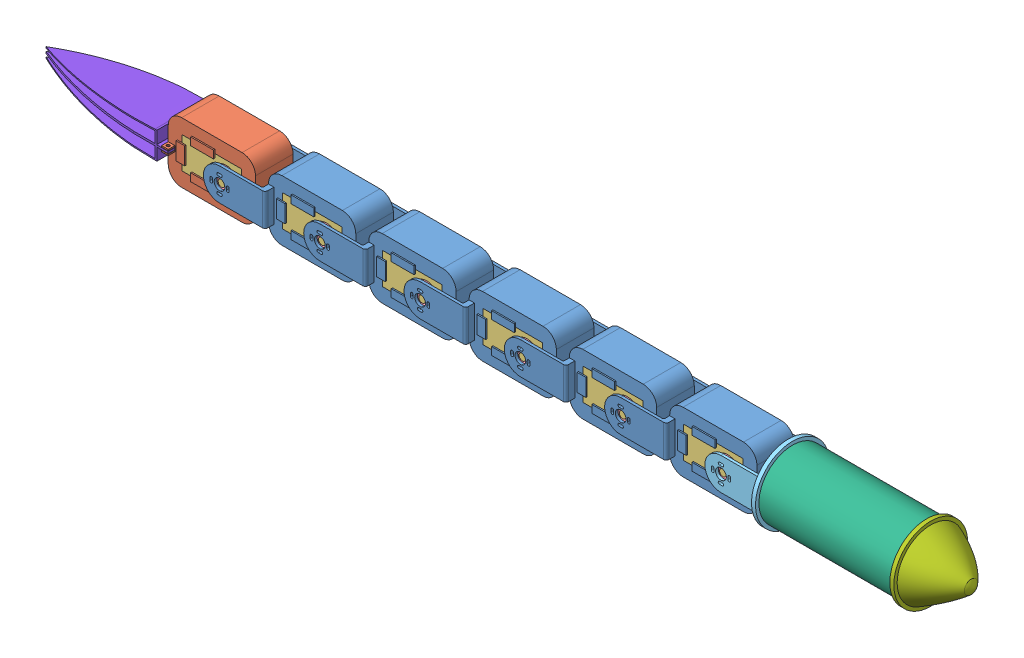
SolidWorks assembly bus_assembly_2, configuration 預設. Lengths in mm.
Overall size (691.28 55 55).
28 component instances, 8 part files, 89 mates.
Components (placement in the parent):
- bus2-1: bus2 [預設] at (12.4546 -2.1213 92.75) size (107 45 40.5)
- bus2-2: bus2 [預設] at (-62.2454 -2.1213 92.75) size (107 45 40.5)
- bus2-3: bus2 [預設] at (-286.3454 -2.1213 92.75) size (107 45 40.5)
- bus2-4: bus2 [預設] at (-136.9454 -2.1213 92.75) size (107 45 40.5)
- bus2-5: bus2 [預設] at (-211.6454 -2.1213 92.75) size (107 45 40.5)
- bus2_tail-1: bus2_tail [預設] at (-361.0454 -2.1213 92.75) size (65 45 38)
- bus_servo-1: bus_servo [預設] at (-368.5322 -13.6144 92.75) x (1 0 0) z (0 -1 0) size (44.4 38 23.4)
- bus_servo_cicrcle1-1: bus_servo_cicrcle1 [預設] at (-376.28 -2.2213 122.25) size (20 20 3)
- bus_servo_cicrcle1-2: bus_servo_cicrcle1 [預設] at (-376.28 -2.1213 88.75) size (20 20 3)
- bus_servo-2: bus_servo [預設] at (-293.8322 -13.6144 92.75) x (1 0 0) z (0 -1 0) size (44.4 38 23.4)
- bus_servo-3: bus_servo [預設] at (-219.1322 -13.6144 92.75) x (1 0 0) z (0 -1 0) size (44.4 38 23.4)
- bus_servo-4: bus_servo [預設] at (-144.4322 9.3718 120.75) x (1 0 0) z (0 1 0) size (44.4 38 23.4)
- bus_servo-5: bus_servo [預設] at (-69.7322 -13.6144 92.75) x (1 0 0) z (0 -1 0) size (44.4 38 23.4)
- bus_servo-6: bus_servo [預設] at (4.9678 -13.6144 92.75) x (1 0 0) z (0 -1 0) size (44.4 38 23.4)
- bus_servo_cicrcle1-3: bus_servo_cicrcle1 [預設] at (-301.58 -2.1213 122.25) size (20 20 3)
- bus_servo_cicrcle1-4: bus_servo_cicrcle1 [預設] at (-301.58 -2.1213 88.75) size (20 20 3)
- bus_servo_cicrcle1-5: bus_servo_cicrcle1 [預設] at (-226.88 -2.1213 88.75) size (20 20 3)
- bus_servo_cicrcle1-6: bus_servo_cicrcle1 [預設] at (-226.88 -2.1213 122.25) size (20 20 3)
- bus_servo_cicrcle1-7: bus_servo_cicrcle1 [預設] at (-152.18 -2.1213 122.25) size (20 20 3)
- bus_servo_cicrcle1-8: bus_servo_cicrcle1 [預設] at (-152.18 -2.1213 88.75) size (20 20 3)
- bus_servo_cicrcle1-9: bus_servo_cicrcle1 [預設] at (-77.48 -2.1213 122.25) size (20 20 3)
- bus_servo_cicrcle1-10: bus_servo_cicrcle1 [預設] at (-77.48 -2.1213 88.75) size (20 20 3)
- bus_servo_cicrcle1-11: bus_servo_cicrcle1 [預設] at (-2.78 -2.1213 88.75) size (20 20 3)
- bus_servo_cicrcle1-12: bus_servo_cicrcle1 [預設] at (-2.78 -2.1213 122.25) x (0 1 0) z (0 0 1) size (20 20 3)
- bus_lib_tail-1: bus_lib_tail [預設] at (30.22 -2.1213 107) x (0 1 0) z (0 0 -1) size (55 65 55)
- bus_body-1: bus_body [預設] at (30.22 -2.1213 107) x (0 -0.027366 -0.999625) z (0 -0.999625 0.027366) size (50 100 50)
- bus_lib_head_1-1: bus_lib_head_1 [預設] at (130.22 -2.1213 107) x (0 1 0) z (0 0 1) size (55 54.98 55)
- bus_final_tail-2: bus_final_tail [預設] at (-425.0707 -2.1213 107.4806) x (-1 0 -0.00071) z (0 -1 0) size (110.1 38.13 25.31)
Mates (geometry in assembly coordinates):
- 重合/共線/共點1: coincident: plane of bus2-1 through (12.4546 -2.1213 120.75) normal (0 0 1); plane of bus2-2 through (-62.2454 -2.1213 120.75) normal (0 0 1)
- 重合/共線/共點2: coincident: plane of bus2-1 through (-47.48 20.3787 120.75) normal (0 1 0); plane of bus2-2 through (-122.18 20.3787 120.75) normal (0 1 0)
- 重合/共線/共點3: coincident: plane of bus2-3 through (-286.3454 -2.1213 120.75) normal (0 0 1); plane of bus2-2 through (-62.2454 -2.1213 120.75) normal (0 0 1)
- 重合/共線/共點4: coincident: plane of bus2-2 through (-122.18 20.3787 120.75) normal (0 1 0); plane of bus2-3 through (-346.28 20.3787 120.75) normal (0 1 0)
- 重合/共線/共點5: coincident: plane of bus2-3 through (-346.28 20.3787 120.75) normal (0 1 0); plane of bus2-4 through (-196.88 20.3787 120.75) normal (0 1 0)
- 重合/共線/共點6: coincident: plane of bus2-3 through (-286.3454 -2.1213 120.75) normal (0 0 1); plane of bus2-4 through (-136.9454 -2.1213 120.75) normal (0 0 1)
- 重合/共線/共點9: coincident: plane of bus2-3 through (-346.28 20.3787 120.75) normal (0 1 0); plane of bus2-5 through (-271.58 20.3787 120.75) normal (0 1 0)
- 重合/共線/共點10: coincident: plane of bus2-3 through (-286.3454 -2.1213 120.75) normal (0 0 1); plane of bus2-5 through (-211.6454 -2.1213 120.75) normal (0 0 1)
- 重合/共線/共點11: coincident: plane of bus2-3 through (-286.3454 -2.1213 120.75) normal (0 0 1); plane of bus2_tail-1 through (-361.0454 -2.1213 120.75) normal (0 0 1)
- 重合/共線/共點12: coincident: plane of bus2-3 through (-346.28 20.3787 120.75) normal (0 1 0); plane of bus2_tail-1 through (-420.98 20.3787 120.75) normal (0 1 0)
- 同軸心1: concentric: cylinder of bus2_tail-1 through (-418.48 2.8787 123.25) axis (0 -1 0) radius 1.1; cylinder of ? through (-418.48 -1.3713 123.25) axis (0 -1 0) radius 1.1
- 同軸心2: concentric: cylinder of bus2_tail-1 through (-418.48 2.8787 90.25) axis (0 -1 0) radius 1.1; cylinder of ? through (-418.48 -1.3713 90.25) axis (0 -1 0) radius 1.1
- 平行相距1: distance = 0.25 mm: line of ? through (-415.9818 -1.3713 125.7518) axis (-1 0 -0.00071); line of bus2_tail-1 through (-420.98 -1.1213 125.75) axis (1 0 0)
- 重合/共線/共點13: coincident: plane of bus2_tail-1 through (-410.68 -13.8213 131.75) normal (0 1 0); plane of bus_servo-1 through (-410.68 -13.8213 120.75) normal (0 -1 0)
- 重合/共線/共點14: coincident: plane of bus2_tail-1 through (-366.28 9.5787 131.75) normal (-1 0 0); plane of bus_servo-1 through (-366.28 9.5787 120.75) normal (1 0 0)
- 重合/共線/共點17: coincident: plane of bus2_tail-1 through (-361.0454 -2.1213 120.75) normal (0 0 1); plane of bus_servo-1 through (-368.5322 -13.6144 120.75) normal (0 0 1)
- 重合/共線/共點18: coincident: plane of bus2-3 through (-377.33 2.9787 86.75) normal (0 1 0); plane of bus_servo_cicrcle1-1 through (-377.33 2.9787 126.25) normal (0 1 0)
- 平行2: parallel: plane of bus2-3 through (-377.33 -9.3213 86.75) normal (0 1 0); plane of bus_servo_cicrcle1-1 through (-377.33 -9.4213 126.25) normal (0 1 0)
- 重合/共線/共點21: coincident: plane of bus2-3 through (-383.48 -1.0713 86.75) normal (1 0 0); plane of bus_servo_cicrcle1-1 through (-383.48 -1.1713 126.25) normal (1 0 0)
- 平行3: parallel: cylinder of bus2-3 through (-376.28 -2.1213 125.25) axis (0 0 1) radius 4; cylinder of bus_servo_cicrcle1-1 through (-376.28 -2.2213 126.25) axis (0 0 -1) radius 4
- 重合/共線/共點22: coincident: plane of bus2-3 through (-376.28 -2.1213 125.25) normal (0 0 -1); plane of bus_servo_cicrcle1-1 through (-376.28 -2.2213 125.25) normal (0 0 1)
- 重合/共線/共點23: coincident: plane of bus2-3 through (-376.28 -2.1213 88.75) normal (0 0 1); plane of bus_servo_cicrcle1-2 through (-376.28 -2.1213 88.75) normal (0 0 -1)
- 同軸心5: concentric: cylinder of bus2-3 through (-376.28 -2.1213 86.75) axis (0 0 1) radius 3.7; cylinder of bus_servo_cicrcle1-2 through (-376.28 -2.1213 92.75) axis (0 0 -1) radius 4
- 同軸心8: concentric: cylinder of bus2-3 through (-376.28 -2.1213 86.75) axis (0 0 1) radius 3.7; cylinder of bus_servo-1 through (-376.28 -2.1213 87.75) axis (0 0 1) radius 2.5
- 重合/共線/共點24: coincident: plane of bus2-3 through (-335.98 -13.8213 131.75) normal (0 1 0); plane of bus_servo-2 through (-335.98 -13.8213 120.75) normal (0 -1 0)
- 重合/共線/共點25: coincident: plane of bus2-3 through (-335.98 9.5787 131.75) normal (1 0 0); plane of bus_servo-2 through (-335.98 9.5787 120.75) normal (-1 0 0)
- 重合/共線/共點26: coincident: plane of bus2-3 through (-286.3454 -2.1213 92.75) normal (0 0 -1); plane of bus_servo-2 through (-293.8322 -13.6144 92.75) normal (0 0 -1)
- 重合/共線/共點27: coincident: plane of bus2-5 through (-261.28 -13.8213 131.75) normal (0 1 0); plane of bus_servo-3 through (-261.28 -13.8213 120.75) normal (0 -1 0)
- 重合/共線/共點28: coincident: plane of bus2-5 through (-261.28 9.5787 131.75) normal (1 0 0); plane of bus_servo-3 through (-261.28 9.5787 120.75) normal (-1 0 0)
- 重合/共線/共點29: coincident: plane of bus2-5 through (-211.6454 -2.1213 92.75) normal (0 0 -1); plane of bus_servo-3 through (-219.1322 -13.6144 92.75) normal (0 0 -1)
- 重合/共線/共點30: coincident: plane of bus2-2 through (-111.88 9.5787 131.75) normal (0 -1 0); plane of bus_servo-4 through (-186.58 9.5787 92.75) normal (0 1 0)
- 重合/共線/共點31: coincident: plane of bus2-4 through (-142.18 9.5787 131.75) normal (-1 0 0); plane of bus_servo-4 through (-142.18 -13.8213 92.75) normal (1 0 0)
- 重合/共線/共點32: coincident: plane of bus2-4 through (-136.9454 -2.1213 120.75) normal (0 0 1); plane of bus_servo-4 through (-144.4322 9.3718 120.75) normal (0 0 1)
- 重合/共線/共點37: coincident: plane of bus2-2 through (-111.88 9.5787 131.75) normal (0 -1 0); plane of bus_servo-5 through (-111.88 9.5787 120.75) normal (0 1 0)
- 重合/共線/共點38: coincident: plane of bus2-2 through (-67.48 9.5787 131.75) normal (-1 0 0); plane of bus_servo-5 through (-67.48 9.5787 120.75) normal (1 0 0)
- 重合/共線/共點40: coincident: plane of bus2-2 through (-62.2454 -2.1213 120.75) normal (0 0 1); plane of bus_servo-5 through (-69.7322 -13.6144 120.75) normal (0 0 1)
- 重合/共線/共點42: coincident: plane of bus2-1 through (12.4546 -2.1213 120.75) normal (0 0 1); plane of bus_servo-6 through (4.9678 -13.6144 120.75) normal (0 0 1)
- 重合/共線/共點43: coincident: plane of bus2-1 through (-37.18 9.5787 131.75) normal (1 0 0); plane of bus_servo-6 through (-37.18 9.5787 120.75) normal (-1 0 0)
- 重合/共線/共點44: coincident: plane of bus2-1 through (-37.18 9.5787 131.75) normal (0 -1 0); plane of bus_servo-6 through (-37.18 9.5787 120.75) normal (0 1 0)
- 同軸心9: concentric: cylinder of bus2-5 through (-301.58 -2.1213 125.25) axis (0 0 1) radius 4; cylinder of bus_servo_cicrcle1-3 through (-301.58 -2.1213 126.25) axis (0 0 -1) radius 4
- 重合/共線/共點45: coincident: plane of bus2-5 through (-301.58 -2.1213 125.25) normal (0 0 -1); plane of bus_servo_cicrcle1-3 through (-301.58 -2.1213 125.25) normal (0 0 1)
- 同軸心10: concentric: cylinder of bus2-5 through (-301.58 -2.1213 86.75) axis (0 0 1) radius 3.7; cylinder of bus_servo_cicrcle1-4 through (-301.58 -2.1213 92.75) axis (0 0 -1) radius 4
- 重合/共線/共點46: coincident: plane of bus2-5 through (-301.58 -2.1213 88.75) normal (0 0 1); plane of bus_servo_cicrcle1-4 through (-301.58 -2.1213 88.75) normal (0 0 -1)
- 同軸心11: concentric: cylinder of bus2-4 through (-226.88 -2.1213 125.25) axis (0 0 1) radius 4; cylinder of bus_servo_cicrcle1-6 through (-226.88 -2.1213 126.25) axis (0 0 -1) radius 4
- 重合/共線/共點47: coincident: plane of bus2-4 through (-226.88 -2.1213 125.25) normal (0 0 -1); plane of bus_servo_cicrcle1-6 through (-226.88 -2.1213 125.25) normal (0 0 1)
- 同軸心12: concentric: cylinder of bus2-4 through (-226.88 -2.1213 86.75) axis (0 0 1) radius 3.7; cylinder of bus_servo_cicrcle1-5 through (-226.88 -2.1213 92.75) axis (0 0 -1) radius 4
- 重合/共線/共點48: coincident: plane of bus2-4 through (-226.88 -2.1213 88.75) normal (0 0 1); plane of bus_servo_cicrcle1-5 through (-226.88 -2.1213 88.75) normal (0 0 -1)
- 同軸心13: concentric: cylinder of bus2-2 through (-152.18 -2.1213 86.75) axis (0 0 1) radius 3.7; cylinder of bus_servo_cicrcle1-8 through (-152.18 -2.1213 92.75) axis (0 0 -1) radius 4
- 重合/共線/共點49: coincident: plane of bus2-2 through (-152.18 -2.1213 88.75) normal (0 0 1); plane of bus_servo_cicrcle1-8 through (-152.18 -2.1213 88.75) normal (0 0 -1)
- 同軸心14: concentric: cylinder of bus2-2 through (-152.18 -2.1213 125.25) axis (0 0 1) radius 4; cylinder of bus_servo_cicrcle1-7 through (-152.18 -2.1213 126.25) axis (0 0 -1) radius 4
- 重合/共線/共點51: coincident: plane of bus2-2 through (-152.18 -2.1213 125.25) normal (0 0 -1); plane of bus_servo_cicrcle1-7 through (-152.18 -2.1213 125.25) normal (0 0 1)
- 重合/共線/共點52: coincident: plane of bus2-5 through (-302.63 -9.3213 125.25) normal (0 1 0); plane of bus_servo_cicrcle1-3 through (-302.63 -9.3213 126.25) normal (0 1 0)
- 平行6: parallel: plane of bus2-5 through (-294.48 -1.0713 125.25) normal (-1 0 0); plane of bus_servo_cicrcle1-3 through (-294.38 -1.0713 126.25) normal (-1 0 0)
- 平行8: parallel: plane of bus2-4 through (-219.78 -1.0713 125.25) normal (-1 0 0); plane of bus_servo_cicrcle1-6 through (-219.68 -1.0713 126.25) normal (-1 0 0)
- 重合/共線/共點56: coincident: plane of bus2-4 through (-227.93 -9.3213 125.25) normal (0 1 0); plane of bus_servo_cicrcle1-6 through (-227.93 -9.3213 126.25) normal (0 1 0)
- 平行9: parallel: plane of bus2-4 through (-219.78 -1.0713 86.75) normal (-1 0 0); plane of bus_servo_cicrcle1-5 through (-219.68 -1.0713 92.75) normal (-1 0 0)
- 平行10: parallel: plane of bus2-4 through (-227.93 4.9787 86.75) normal (0 -1 0); plane of bus_servo_cicrcle1-5 through (-227.93 5.0787 92.75) normal (0 -1 0)
- 平行11: parallel: line of bus2-2 through (-153.23 2.9787 127.25) axis (1 0 0); plane of bus_servo_cicrcle1-7 through (-153.23 3.0787 126.25) normal (0 1 0)
- 平行12: parallel: plane of bus2-2 through (-145.08 -1.0713 125.25) normal (-1 0 0); plane of bus_servo_cicrcle1-7 through (-144.98 -1.0713 126.25) normal (-1 0 0)
- 重合/共線/共點61: coincident: plane of bus2-2 through (-153.23 -7.3213 86.75) normal (0 -1 0); plane of bus_servo_cicrcle1-8 through (-153.23 -7.3213 92.75) normal (0 -1 0)
- 平行13: parallel: plane of bus2-2 through (-145.08 -1.0713 86.75) normal (-1 0 0); plane of bus_servo_cicrcle1-8 through (-144.98 -1.0713 92.75) normal (-1 0 0)
- 重合/共線/共點63: coincident: plane of bus2-1 through (-77.48 -2.1213 88.75) normal (0 0 1); plane of bus_servo_cicrcle1-10 through (-77.48 -2.1213 88.75) normal (0 0 -1)
- 同軸心15: concentric: cylinder of bus2-1 through (-77.48 -2.1213 86.75) axis (0 0 1) radius 3.7; cylinder of bus_servo_cicrcle1-10 through (-77.48 -2.1213 92.75) axis (0 0 -1) radius 4
- 平行14: parallel: plane of bus2-1 through (-78.53 2.9787 86.75) normal (0 1 0); plane of bus_servo_cicrcle1-10 through (-78.53 3.0787 92.75) normal (0 1 0)
- 同軸心16: concentric: cylinder of bus2-1 through (-77.48 -2.1213 125.25) axis (0 0 1) radius 4; cylinder of bus_servo_cicrcle1-9 through (-77.48 -2.1213 126.25) axis (0 0 -1) radius 4
- 重合/共線/共點65: coincident: plane of bus2-1 through (-77.48 -2.1213 125.25) normal (0 0 -1); plane of bus_servo_cicrcle1-9 through (-77.48 -2.1213 125.25) normal (0 0 1)
- 平行15: parallel: plane of bus2-1 through (-78.53 2.9787 125.25) normal (0 1 0); plane of bus_servo_cicrcle1-9 through (-78.53 3.0787 126.25) normal (0 1 0)
- 同軸心17: concentric: cylinder of bus_servo-2 through (-301.58 -2.1213 120.75) axis (0 0 1) radius 2.5; cylinder of bus_servo_cicrcle1-3 through (-301.58 -2.1213 126.25) axis (0 0 -1) radius 4
- 同軸心18: concentric: cylinder of bus_servo-3 through (-226.88 -2.1213 120.75) axis (0 0 1) radius 2.5; cylinder of bus_servo_cicrcle1-6 through (-226.88 -2.1213 126.25) axis (0 0 -1) radius 4
- 同軸心37: concentric: cylinder of bus_servo-4 through (-152.18 -2.1213 125.75) axis (0 0 -1) radius 2.5; cylinder of bus_servo_cicrcle1-7 through (-152.18 -2.1213 126.25) axis (0 0 -1) radius 4
- 同軸心39: concentric: cylinder of bus_servo-5 through (-77.48 -2.1213 87.75) axis (0 0 1) radius 2.5; cylinder of bus_servo_cicrcle1-10 through (-77.48 -2.1213 92.75) axis (0 0 -1) radius 4
- 重合/共線/共點76: coincident: plane of bus_servo_cicrcle1-12 through (-2.78 -2.1213 125.25) normal (0 0 1); plane of bus_lib_tail-1 through (-2.78 -2.1213 125.25) normal (0 0 -1)
- 重合/共線/共點77: coincident: plane of bus_servo_cicrcle1-11 through (-2.78 -2.1213 88.75) normal (0 0 -1); plane of bus_lib_tail-1 through (-2.78 -2.1213 88.75) normal (0 0 1)
- 同軸心41: concentric: cylinder of bus_servo_cicrcle1-11 through (-2.78 -2.1213 92.75) axis (0 0 -1) radius 4; cylinder of bus_lib_tail-1 through (-2.78 -2.1213 88.75) axis (0 0 -1) radius 4
- 重合/共線/共點78: coincident: plane of bus_servo_cicrcle1-11 through (-7.98 -1.0713 92.75) normal (-1 0 0); plane of bus_lib_tail-1 through (-7.98 -3.1713 88.75) normal (-1 0 0)
- 重合/共線/共點79: coincident: plane of bus_servo_cicrcle1-11 through (-3.83 -9.3213 92.75) normal (0 1 0); plane of bus_lib_tail-1 through (-1.73 -9.3213 88.75) normal (0 1 0)
- 重合/共線/共點80: coincident: plane of bus_servo_cicrcle1-12 through (-3.83 -9.3213 126.25) normal (0 1 0); plane of bus_lib_tail-1 through (-1.73 -9.3213 127.25) normal (0 1 0)
- 重合/共線/共點81: coincident: plane of bus_servo_cicrcle1-12 through (4.42 -3.1713 126.25) normal (-1 0 0); plane of bus_lib_tail-1 through (4.42 -3.1713 127.25) normal (-1 0 0)
- 同軸心42: concentric: cylinder of bus_servo_cicrcle1-12 through (-2.78 -2.1213 126.25) axis (0 0 -1) radius 4; cylinder of bus_lib_tail-1 through (-2.78 -2.1213 127.25) axis (0 0 -1) radius 4
- 同軸心43: concentric: cylinder of bus_servo-6 through (-2.78 -2.1213 120.75) axis (0 0 1) radius 2.5; cylinder of bus_servo_cicrcle1-12 through (-2.78 -2.1213 126.25) axis (0 0 -1) radius 4
- 重合/共線/共點82: coincident: plane of bus2-1 through (-47.48 9.8787 126.75) normal (0 1 0); plane of bus_lib_tail-1 through (27.22 9.8787 127.25) normal (0 1 0)
- 重合/共線/共點83: coincident: plane of bus2-1 through (-77.48 -2.1213 127.25) normal (0 0 1); plane of bus_lib_tail-1 through (-2.78 -2.1213 127.25) normal (0 0 1)
- 同軸心44: concentric: cylinder of bus_lib_tail-1 through (35.22 -2.1213 107) axis (1 0 0) radius 21.75; cylinder of bus_body-1 through (130.22 -2.1213 107) axis (-1 0 0) radius 22
- 重合/共線/共點84: coincident: plane of bus_lib_tail-1 through (30.22 -2.1213 107) normal (1 0 0); plane of bus_body-1 through (30.22 -2.1213 107) normal (-1 0 0)
- 同軸心45: concentric: cylinder of bus_body-1 through (130.22 -2.1213 107) axis (-1 0 0) radius 22; cylinder of bus_lib_head_1-1 through (115.72 -2.1213 107) axis (1 0 0) radius 21.75
- 重合/共線/共點85: coincident: plane of bus_body-1 through (130.22 -2.1213 107) normal (1 0 0); plane of bus_lib_head_1-1 through (130.22 -2.1213 107) normal (-1 0 0)
- 同軸心46: concentric: cylinder of bus2_tail-1 through (-418.48 2.8787 123.25) axis (0 -1 0) radius 1.1; cylinder of bus_final_tail-2 through (-418.48 -1.3713 123.25) axis (0 -1 0) radius 1.1
- 同軸心47: concentric: cylinder of bus2_tail-1 through (-418.48 2.8787 90.25) axis (0 -1 0) radius 1.1; cylinder of bus_final_tail-2 through (-418.48 -1.3713 90.25) axis (0 -1 0) radius 1.1
- 平行相距2: distance = 0.25 mm: plane of bus_final_tail-2 through (-425.0707 -1.3713 107.4806) normal (0 1 0); plane of bus2_tail-1 through (-361.0454 -1.1213 92.75) normal (0 -1 0)
